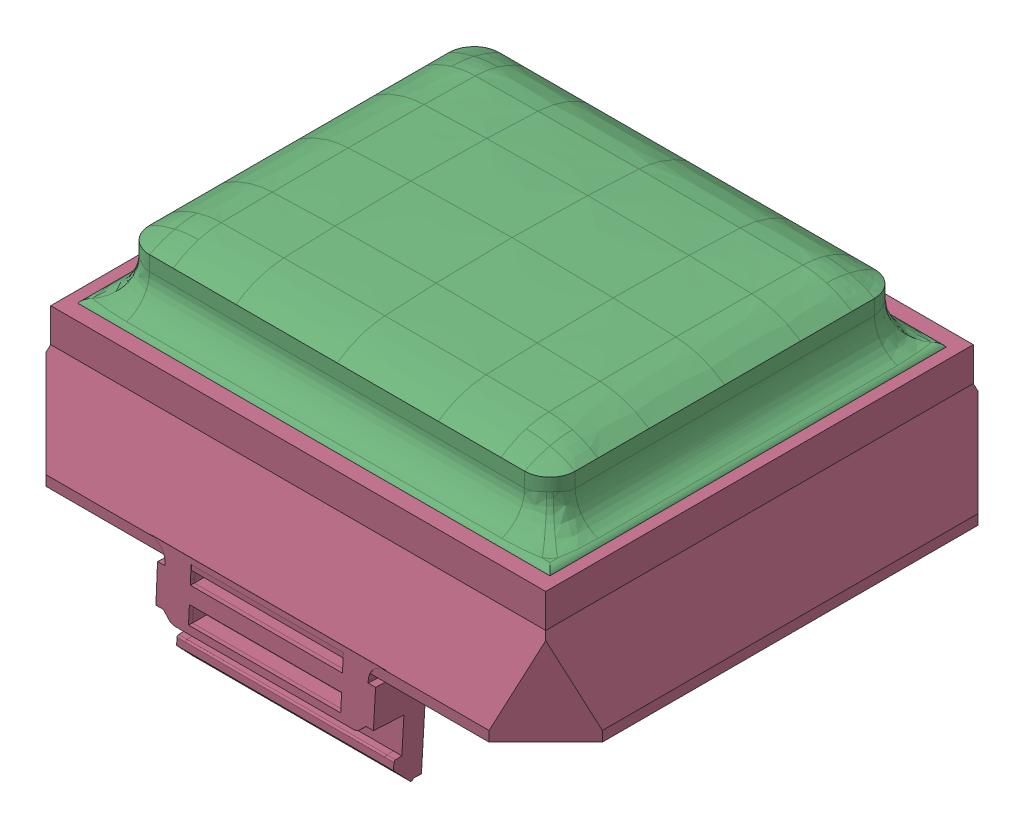
SolidWorks assembly DoubleDotV2, configuration 默认. Lengths in mm.
Overall size (33 17.5 29.5).
6 component instances, 5 part files, 23 mates.
Components (placement in the parent):
- Lens-1: Lens [默认] at origin size (28.33 2.18 23.83)
- InsideSkin-1: InsideSkin [默认] at (0.0001 0 0.2499) size (23.8 5.48 19.29)
- Topskin-1: Topskin [默认] at (0.0001 2 0.2499) size (28.02 6.25 23.52) (hidden)
- Supportbase-2: Supportbase [默认] at origin size (33 14.02 29.5)
- Dor-1: Dor [默认] at (-1.2499 23.9 -0.9614) x (-1 0 0) z (0 -1 0) size (18.98 16.99 1.63)
- Dor-2: Dor [默认] at (-1.2499 22.7 -0.9614) x (-1 0 0) z (0 -1 0) size (18.98 16.99 1.63)
Mates (geometry in assembly coordinates):
- 同心2: concentric anti-aligned: cylinder of InsideSkin-1 through (10.8751 17.7531 8.6249) axis (0 1 0) radius 0.7; cylinder of Board3Con1612611OriginalSkin_TOP-1 through (10.8751 24 8.6249) axis (0 -1 0) radius 0.7
- 同心3: concentric anti-aligned: cylinder of InsideSkin-1 through (10.8751 17.7531 -9.1251) axis (0 1 0) radius 0.7; cylinder of Board3Con1612611OriginalSkin_TOP-1 through (10.8751 24 -9.1251) axis (0 -1 0) radius 0.7
- 重合4: coincident aligned: plane of InsideSkin-1 through (10.8751 19 -9.1251) normal (0 -1 0); plane of Board3Con1612611OriginalSkin_TOP-1 through (0.0001 19 0.2499) normal (0 -1 0)
- 重合6: coordinate: point of NewContiSupportBase-2
- 重合7: coincident anti-aligned: plane of lensall-1 through (13.75 19 -11.5) normal (0.939693 0.34202 0); plane of NewContiSupportBase-2 through (13.75 19 12.7803) normal (-0.939693 -0.34202 0)
- 同心5: concentric aligned: cylinder of lensall-1 through (13.3294 18.6938 -11.0794) axis (-0.323616 0.889126 0.323616) radius 0.5; cylinder of NewContiSupportBase-2 through (10.7866 25.6801 -8.5366) axis (-0.323616 0.889126 0.323616) radius 0.5
- 重合8: coincident anti-aligned: plane of lensall-1 through (0 18 0) normal (0 -1 0); plane of NewContiSupportBase-2 through (0 18 0) normal (0 1 0)
- 重合9: coincident anti-aligned: plane of lensall-1 through (0 19 0) normal (0 1 0); plane of Board3Con1612611OriginalSkin_TOP-1 through (0.0001 19 0.2499) normal (0 -1 0)
- 重合10: coincident anti-aligned: plane of Board3Con1612611OriginalSkin_TOP-1 through (0.0001 19 11.7499) normal (0 0 1); plane of NewContiSupportBase-2 through (-13.5999 21 11.7499) normal (0 0 -1)
- 重合11: coincident anti-aligned: plane of Board3Con1612611OriginalSkin_TOP-1 through (14.0001 19 0.2499) normal (1 0 0); plane of NewContiSupportBase-2 through (14.0001 21 11.7499) normal (-1 0 0)
- 平行1: parallel: plane of InsideSkin-1 through (-11.3749 17.7531 9.3249) normal (0 0 1); line of Dor-1 through (8.7251 23.9 6.9749) axis (-1 0 0)
- 平行2: parallel: plane of InsideSkin-1 through (-12.0749 17.7531 -9.1251) normal (-1 0 0); line of Dor-1 through (-12.2749 23.9 -8.0251) axis (0 0 1)
- 距离1: distance = 1.8 mm: line of Dor-1 through (8.7251 23.9 -8.0251) axis (-1 0 0); plane of InsideSkin-1 through (-11.3749 17.7531 -9.8251) normal (0 0 -1)
- 平行3: parallel anti-aligned: line of Supportbase-2 through (14.6801 19 12.1801) axis (0 0 -1); line of Dor-1 through (9.9597 23.9 -9.2955) axis (0 0 1)
- 距离2: distance = 5 mm: plane of Lens-1 through (0 19 0) normal (0 1 0); line of Dor-1 through (-12.2749 23.9 -8.0251) axis (0 0 1)
- 距离3: distance = 2.85 mm: plane of InsideSkin-1 through (11.5751 17.7531 -9.1251) normal (1 0 0); line of Dor-1 through (8.7251 23.9 -8.0251) axis (0 0 1)
- 平行4: parallel aligned: line of Supportbase-2 through (14.1801 19 -12.6801) axis (-1 0 0); line of Dor-1 through (9.9597 23.9 10.7045) axis (-1 0 0)
- 距离5: distance = 4.9 mm: plane of Lens-1 through (0 19 0) normal (0 1 0); line of Dor-1 through (8.7251 23.9 -8.0251) axis (0 0 1)
- 平行5: parallel aligned: line of Dor-1 through (-9.2581 23.9 7.9601) axis (1 0 0); line of Dor-2 through (-9.2581 22.7 7.9601) axis (1 0 0)
- 平行6: parallel aligned: line of Dor-1 through (-9.2581 23.9 -8.0251) axis (0 0 1); line of Dor-2 through (-9.2581 22.7 -8.0251) axis (0 0 1)
- 距离6: distance = 3.7 mm: plane of Lens-1 through (0 19 0) normal (0 1 0); line of Dor-2 through (8.7251 22.7 -8.0251) axis (0 0 1)
- 距离7: distance = 1.2 mm: line of Dor-2 through (-9.2581 22.7 -8.0251) axis (1 0 0); line of Dor-1 through (-9.2581 23.9 -8.0251) axis (1 0 0)
- 距离8: distance = 1.2 mm: line of Dor-2 through (8.7251 22.7 -8.0251) axis (0 0 1); line of Dor-1 through (8.7251 23.9 -8.0251) axis (0 0 1)
